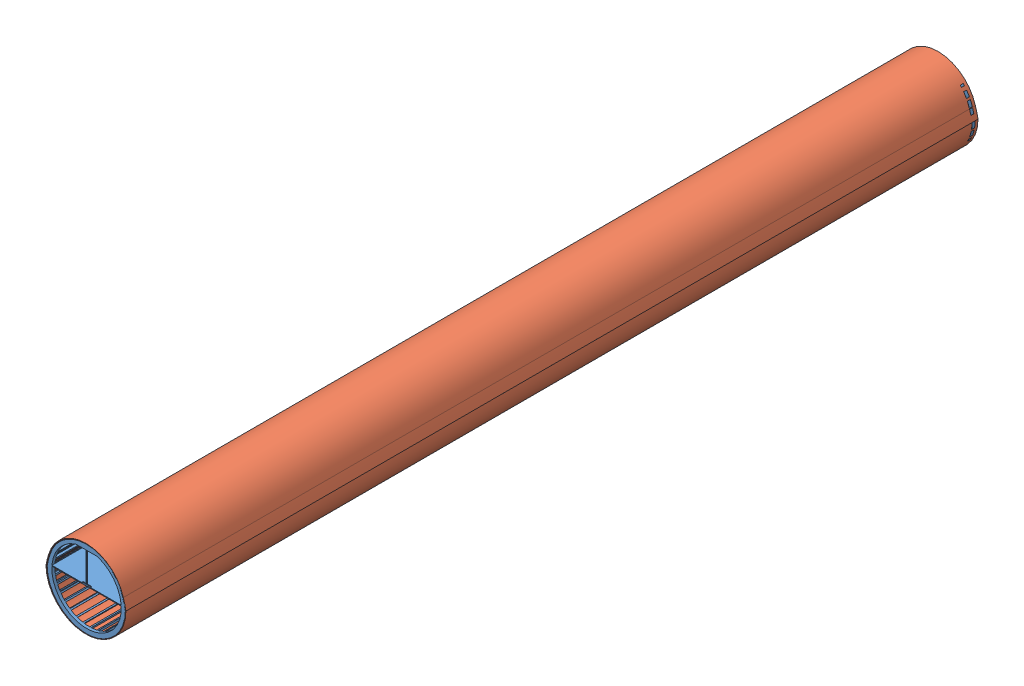
SolidWorks assembly Fuselage_Assembly, configuration Default. Lengths in mm.
Overall size (1360 1340 14500).
2 component instances, 2 part files, 1 mates.
Components (placement in the parent):
- Fuselage-1: Fuselage [Default] at (5058.1744 8248.6337 18019.6175) size (1340 1320 14450)
- Fuselage_Skin-1: Fuselage_Skin [Default] at (5048.1752 8247.6107 18019.6175) size (1360 1340 14500)
Mates (geometry in assembly coordinates):
- Coincident1: coincident: point of Fuselage_Skin-1; point of Fuselage-1
